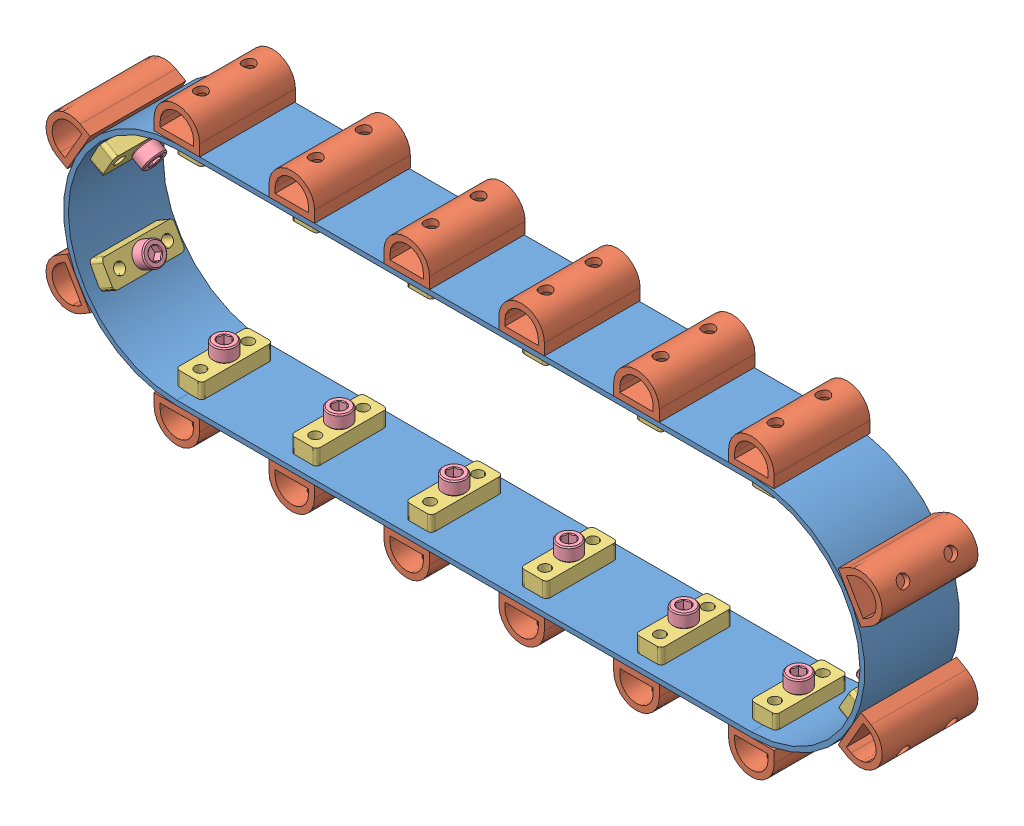
SolidWorks assembly tread, configuration Default. Lengths in mm.
Overall size (178.18 61.66 20).
65 component instances, 4 part files, 7 mates.
Components (placement in the parent):
- tread_base-1: tread_base [Default] at origin size (167.39 47.38 19.81)
- D-Lug_Terrain-1: D-Lug_Terrain [Default] at (0 48.7584 -10.094) size (9.53 7.14 20)
- D-Lug_Terrain-2: D-Lug_Terrain [Default] at (-22.5771 35.7234 -10.094) x (0.5 0.866025 0) z (0 0 1) size (9.53 7.14 20)
- D-Lug_Terrain-3: D-Lug_Terrain [Default] at (-22.5771 9.6536 -10.094) x (-0.5 0.866025 0) z (0 0 1) size (9.53 7.14 20)
- D-Lug_Terrain-4: D-Lug_Terrain [Default] at (0 -3.3813 -10.094) x (-1 0 0) z (0 0 1) size (9.53 7.14 20)
- D-Lug_Terrain-6: D-Lug_Terrain [Default] at (24.003 48.7584 -10.094) size (9.53 7.14 20)
- D-Lug_Terrain-7: D-Lug_Terrain [Default] at (48.006 48.7584 -10.094) size (9.53 7.14 20)
- D-Lug_Terrain-8: D-Lug_Terrain [Default] at (72.009 48.7584 -10.094) size (9.53 7.14 20)
- D-Lug_Terrain-9: D-Lug_Terrain [Default] at (96.012 48.7584 -10.094) size (9.53 7.14 20)
- D-Lug_Terrain-10: D-Lug_Terrain [Default] at (120.015 48.7584 -10.094) size (9.53 7.14 20)
- D-Lug_Terrain-11: D-Lug_Terrain [Default] at (24.003 -3.3813 -10.094) x (-1 0 0) z (0 0 1) size (9.53 7.14 20)
- D-Lug_Terrain-12: D-Lug_Terrain [Default] at (48.006 -3.3813 -10.094) x (-1 0 0) z (0 0 1) size (9.53 7.14 20)
- D-Lug_Terrain-13: D-Lug_Terrain [Default] at (72.009 -3.3813 -10.094) x (-1 0 0) z (0 0 1) size (9.53 7.14 20)
- D-Lug_Terrain-14: D-Lug_Terrain [Default] at (96.012 -3.3813 -10.094) x (-1 0 0) z (0 0 1) size (9.53 7.14 20)
- D-Lug_Terrain-15: D-Lug_Terrain [Default] at (142.5921 35.7234 -10.094) x (0.5 -0.866025 0) z (0 0 1) size (9.53 7.14 20)
- D-Lug_Terrain-16: D-Lug_Terrain [Default] at (142.5921 9.6536 -10.094) x (-0.5 -0.866025 0) z (0 0 1) size (9.53 7.14 20)
- D-Lug_Terrain-17: D-Lug_Terrain [Default] at (120.015 -3.3813 -10.094) x (-1 0 0) z (0 0 1) size (9.53 7.14 20)
- Drive Lug_x-1: Drive Lug_x [Default] at (-2.7045 0 0) size (5.84 6.24 14.92)
  - Drive Lug_x-1: Drive Lug_x [Default] at origin size (5.41 3.2 14.92)
  - 97334A104_NYLON SOCKET HEAD CAP SCREW-1: 97334A104_NYLON SOCKET HEAD CAP SCREW [97334A104] at (2.7045 0.0254 0) x (0.302379 0 0.953188) z (0 -1 0) size (4.65 4.65 6.24)
- Drive Lug_x-2: Drive Lug_x [Default] at (-21.0011 13.6864 0) x (0.5 -0.866025 0) z (0 0 1) size (5.84 6.24 14.92)
  - Drive Lug_x-1: Drive Lug_x [Default] at origin size (5.41 3.2 14.92)
  - 97334A104_NYLON SOCKET HEAD CAP SCREW-1: 97334A104_NYLON SOCKET HEAD CAP SCREW [97334A104] at (2.7045 0.0254 0) x (0.302379 0 0.953188) z (0 -1 0) size (4.65 4.65 6.24)
- Drive Lug_x-3: Drive Lug_x [Default] at (-18.2966 36.375 0) x (-0.5 -0.866025 0) z (0 0 1) size (5.84 6.24 14.92)
  - Drive Lug_x-1: Drive Lug_x [Default] at origin size (5.41 3.2 14.92)
  - 97334A104_NYLON SOCKET HEAD CAP SCREW-1: 97334A104_NYLON SOCKET HEAD CAP SCREW [97334A104] at (2.7045 0.0254 0) x (0.302379 0 0.953188) z (0 -1 0) size (4.65 4.65 6.24)
- Drive Lug_x-4: Drive Lug_x [Default] at (2.7045 45.3771 0) x (-1 0 0) z (0 0 1) size (5.84 6.24 14.92)
  - Drive Lug_x-1: Drive Lug_x [Default] at origin size (5.41 3.2 14.92)
  - 97334A104_NYLON SOCKET HEAD CAP SCREW-1: 97334A104_NYLON SOCKET HEAD CAP SCREW [97334A104] at (2.7045 0.0254 0) x (0.302379 0 0.953188) z (0 -1 0) size (4.65 4.65 6.24)
- Drive Lug_x-17: Drive Lug_x [Default] at (21.2985 0 0) size (5.84 6.24 14.92)
  - Drive Lug_x-1: Drive Lug_x [Default] at origin size (5.41 3.2 14.92)
  - 97334A104_NYLON SOCKET HEAD CAP SCREW-1: 97334A104_NYLON SOCKET HEAD CAP SCREW [97334A104] at (2.7045 0.0254 0) x (0.302379 0 0.953188) z (0 -1 0) size (4.65 4.65 6.24)
- Drive Lug_x-18: Drive Lug_x [Default] at (45.3015 0 0) size (5.84 6.24 14.92)
  - Drive Lug_x-1: Drive Lug_x [Default] at origin size (5.41 3.2 14.92)
  - 97334A104_NYLON SOCKET HEAD CAP SCREW-1: 97334A104_NYLON SOCKET HEAD CAP SCREW [97334A104] at (2.7045 0.0254 0) x (0.302379 0 0.953188) z (0 -1 0) size (4.65 4.65 6.24)
- Drive Lug_x-19: Drive Lug_x [Default] at (69.3045 0 0) size (5.84 6.24 14.92)
  - Drive Lug_x-1: Drive Lug_x [Default] at origin size (5.41 3.2 14.92)
  - 97334A104_NYLON SOCKET HEAD CAP SCREW-1: 97334A104_NYLON SOCKET HEAD CAP SCREW [97334A104] at (2.7045 0.0254 0) x (0.302379 0 0.953188) z (0 -1 0) size (4.65 4.65 6.24)
- Drive Lug_x-20: Drive Lug_x [Default] at (93.3075 0 0) size (5.84 6.24 14.92)
  - Drive Lug_x-1: Drive Lug_x [Default] at origin size (5.41 3.2 14.92)
  - 97334A104_NYLON SOCKET HEAD CAP SCREW-1: 97334A104_NYLON SOCKET HEAD CAP SCREW [97334A104] at (2.7045 0.0254 0) x (0.302379 0 0.953188) z (0 -1 0) size (4.65 4.65 6.24)
- Drive Lug_x-21: Drive Lug_x [Default] at (117.3105 0 0) size (5.84 6.24 14.92)
  - Drive Lug_x-1: Drive Lug_x [Default] at origin size (5.41 3.2 14.92)
  - 97334A104_NYLON SOCKET HEAD CAP SCREW-1: 97334A104_NYLON SOCKET HEAD CAP SCREW [97334A104] at (2.7045 0.0254 0) x (0.302379 0 0.953188) z (0 -1 0) size (4.65 4.65 6.24)
- Drive Lug_x-22: Drive Lug_x [Default] at (138.3116 9.0021 0) x (0.5 0.866025 0) z (0 0 1) size (5.84 6.24 14.92)
  - Drive Lug_x-1: Drive Lug_x [Default] at origin size (5.41 3.2 14.92)
  - 97334A104_NYLON SOCKET HEAD CAP SCREW-1: 97334A104_NYLON SOCKET HEAD CAP SCREW [97334A104] at (2.7045 0.0254 0) x (0.302379 0 0.953188) z (0 -1 0) size (4.65 4.65 6.24)
- Drive Lug_x-23: Drive Lug_x [Default] at (141.0161 31.6907 0) x (-0.5 0.866025 0) z (0 0 1) size (5.84 6.24 14.92)
  - Drive Lug_x-1: Drive Lug_x [Default] at origin size (5.41 3.2 14.92)
  - 97334A104_NYLON SOCKET HEAD CAP SCREW-1: 97334A104_NYLON SOCKET HEAD CAP SCREW [97334A104] at (2.7045 0.0254 0) x (0.302379 0 0.953188) z (0 -1 0) size (4.65 4.65 6.24)
- Drive Lug_x-24: Drive Lug_x [Default] at (122.7195 45.3771 0) x (-1 0 0) z (0 0 1) size (5.84 6.24 14.92)
  - Drive Lug_x-1: Drive Lug_x [Default] at origin size (5.41 3.2 14.92)
  - 97334A104_NYLON SOCKET HEAD CAP SCREW-1: 97334A104_NYLON SOCKET HEAD CAP SCREW [97334A104] at (2.7045 0.0254 0) x (0.302379 0 0.953188) z (0 -1 0) size (4.65 4.65 6.24)
- Drive Lug_x-13: Drive Lug_x [Default] at (26.7075 45.3771 0) x (-1 0 0) z (0 0 1) size (5.84 6.24 14.92)
  - Drive Lug_x-1: Drive Lug_x [Default] at origin size (5.41 3.2 14.92)
  - 97334A104_NYLON SOCKET HEAD CAP SCREW-1: 97334A104_NYLON SOCKET HEAD CAP SCREW [97334A104] at (2.7045 0.0254 0) x (0.302379 0 0.953188) z (0 -1 0) size (4.65 4.65 6.24)
- Drive Lug_x-14: Drive Lug_x [Default] at (50.7105 45.3771 0) x (-1 0 0) z (0 0 1) size (5.84 6.24 14.92)
  - Drive Lug_x-1: Drive Lug_x [Default] at origin size (5.41 3.2 14.92)
  - 97334A104_NYLON SOCKET HEAD CAP SCREW-1: 97334A104_NYLON SOCKET HEAD CAP SCREW [97334A104] at (2.7045 0.0254 0) x (0.302379 0 0.953188) z (0 -1 0) size (4.65 4.65 6.24)
- Drive Lug_x-15: Drive Lug_x [Default] at (74.7135 45.3771 0) x (-1 0 0) z (0 0 1) size (5.84 6.24 14.92)
  - Drive Lug_x-1: Drive Lug_x [Default] at origin size (5.41 3.2 14.92)
  - 97334A104_NYLON SOCKET HEAD CAP SCREW-1: 97334A104_NYLON SOCKET HEAD CAP SCREW [97334A104] at (2.7045 0.0254 0) x (0.302379 0 0.953188) z (0 -1 0) size (4.65 4.65 6.24)
- Drive Lug_x-16: Drive Lug_x [Default] at (98.7165 45.3771 0) x (-1 0 0) z (0 0 1) size (5.84 6.24 14.92)
  - Drive Lug_x-1: Drive Lug_x [Default] at origin size (5.41 3.2 14.92)
  - 97334A104_NYLON SOCKET HEAD CAP SCREW-1: 97334A104_NYLON SOCKET HEAD CAP SCREW [97334A104] at (2.7045 0.0254 0) x (0.302379 0 0.953188) z (0 -1 0) size (4.65 4.65 6.24)
Mates (geometry in assembly coordinates):
- Coincident2: coincident: plane of tread_base-1 through (0 46.3771 9.906) normal (0 1 0); plane of D-Lug_Terrain-1 through (-4.7625 46.3771 9.906) normal (0 -1 0)
- Coincident3: coincident: plane of tread_base-1 through (120.015 22.6885 9.906) normal (0 0 1); plane of D-Lug_Terrain-1 through (0 48.7584 9.906) normal (0 0 1)
- Coincident6: coincident: point of tread_base-1; point of D-Lug_Terrain-1
- Coincident7: coincident: plane of tread_base-1 through (0 0 9.906) normal (0 1 0); plane of Drive Lug_x-1/Drive Lug_x-1 through (-2.7045 0 7.46) normal (0 -1 0)
- Coincident8: coincident: line of tread_base-1 through (120.015 0 0) axis (0 1 0); point of Drive Lug_x-1/Drive Lug_x-1
- Parallel2: parallel: plane of tread_base-1 through (120.015 22.6885 9.906) normal (0 0 1); plane of Drive Lug_x-1/Drive Lug_x-1 through (-2.7045 0 7.46) normal (0 0 1)
- Coincident13: coincident: line of tread_base-1 through (0 0 9.906) axis (0 0 -1); point of Drive Lug_x-1/Drive Lug_x-1
